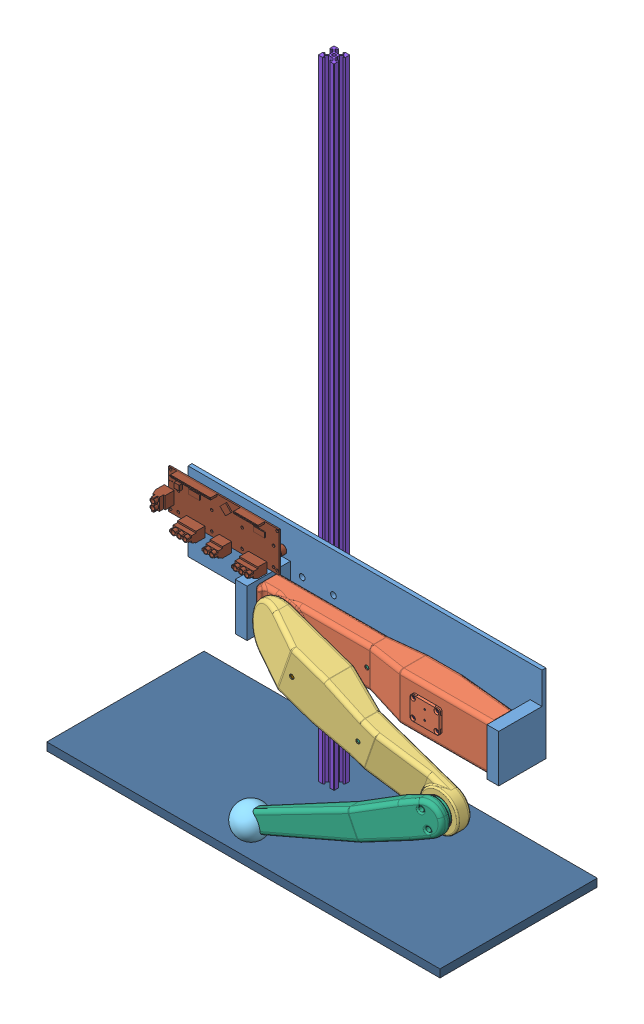
SolidWorks assembly TEST_BENCH_LEG, configuration Default. Lengths in mm.
Overall size (526.75 826.68 209.73).
115 component instances, 48 part files, 14 mates.
Components (placement in the parent):
- FRAME_TEST_BENCH-1: FRAME_TEST_BENCH [Default] at (203.4676 256.1925 358.833) size (450 100 60)
- LIMB_ASSEMBLY-1: LIMB_ASSEMBLY [Default] at (117.0863 75.028 160.078) size (320 252.77 98.98)
  - SHOULDER_ASSEMBLY-1: SHOULDER_ASSEMBLY [Default] at (272.4901 -79.7457 65.6363) x (-1 0 0) z (0 1 0) size (320 40.5 60)
    - SHOULDER_MODULE-1: SHOULDER_MODULE [Default] at (56.0604 170.3399 241.2953) size (320 39 60)
    - Reduction_module-1: Reduction_module [Default] at (136.5679 123.0145 230.5234) x (0.986065 0 -0.166359) z (0.166359 0 0.986065) size (46.5 23.1 46.5)
      - BEARING_MR84-2RS_4x8x2mm.step-2: BEARING_MR84-2RS_4x8x2mm.step [Default] at (6.5822 30.8254 12.0346) x (0.704016 0 0.710185) z (0 -1 0) size (8 8 2)
      - DRIVEN_PULLEY_FIRST_REDUCTION-1: DRIVEN_PULLEY_FIRST_REDUCTION [По умолчанию] at (6.5822 31.8754 12.0346) x (0.983912 0 0.178656) z (0 1 0) size (40 40 8.1)
      - GT2_driving_pulley_second_reduction-1: GT2_driving_pulley_second_reduction [Default] at (6.5822 37.4254 12.0346) x (0.960792 0 -0.27727) z (0 -1 0) size (16 16 16)
      - REDUCTION_SHAFT-1: REDUCTION_SHAFT [Default] at (6.5822 41.3754 12.0346) size (4 23.1 4)
      - BEARING_MR84-2RS_4x8x2mm.step-3: BEARING_MR84-2RS_4x8x2mm.step [Default] at (6.5822 51.9254 12.0346) x (-0.641213 0 -0.767363) z (0 -1 0) size (8 8 2)
      - bearing_spacer_1mm-1: bearing_spacer_1mm [Default] at (6.5822 31.8254 12.0346) x (0.908927 0 0.416955) z (-0.416955 0 0.908927) size (5.2 1 5.2)
      - bearing_spacer_1mm-2: bearing_spacer_1mm [Default] at (6.5822 49.9254 12.0346) size (5.2 1 5.2)
    - Actuator_Module-1: Actuator_Module [Default] at (32.1417 199.8019 282.6675) x (1 0 0) z (0 0 -1) size (50.08 34 54.53)
      - BLDC_Motor_5010-1: BLDC_Motor_5010 [Varsayılan] at (23.9187 12.962 41.3722) size (50.08 20 54.53)
      - MOTOR_SHAFT-1: MOTOR_SHAFT [Default] at (23.9187 29.962 41.3722) x (0.617706 0 0.786409) z (-0.786409 0 0.617706) size (4 34 4)
      - Gates_2GT_20T_Toothed_Pulley-1: Gates_2GT_20T_Toothed_Pulley [Výchozí] at (23.9187 27.862 41.3722) x (0.949687 0 0.313202) z (-0.313202 0 0.949687) size (15 9.4 15)
      - BEARING_MR84-2RS_4x8x2mm.step-4: BEARING_MR84-2RS_4x8x2mm.step [Default] at (23.9187 45.962 41.3722) x (1 0 0) z (0 -1 0) size (8 8 2)
      - pulley-motor-interface-1: pulley-motor-interface [Default] at (23.9187 32.962 41.3722) size (20 2.5 20)
      - bearing_spacer_1mm-1: bearing_spacer_1mm [Default] at (23.9187 43.862 41.3722) size (5.2 1 5.2)
    - Second_reduction_module-1: Second_reduction_module [Default] at (254.9841 185.8856 208.4174) x (-0.999944 0 -0.01057) z (-0.01057 0 0.999944) size (37.7 15.5 37.7)
      - DRIVEN_PULLEY_SECOND_REDUCTION-1: DRIVEN_PULLEY_SECOND_REDUCTION [По умолчанию] at (8.5756 23.3079 32.9704) x (-1 0 0) z (0 -1 0) size (37.7 37.7 15.5)
      - Bearings_6706-2RS.stp-1: Bearings_6706-2RS.stp [Default] at (8.5756 23.7518 32.9704) x (0 1 0) z (0 0 -1) size (3.99 37.01 37.01)
      - Bearings_6706-2RS.stp-2: Bearings_6706-2RS.stp [Default] at (8.5756 12.264 32.9704) x (0 1 0) z (0 0 1) size (3.99 37.01 37.01)
    - Belt-firstt-reduction-1: Belt-firstt-reduction [Default] at (56.0604 157.2025 241.2953) x (0.999993 0 0.003757) z (0 1 0) size (115.2 39.26 6)
    - Belt-second-reduction-1: Belt-second-reduction [Default] at (145.0604 164.4284 241.2953) x (1 0 0.000939) z (-0.000939 0 1) size (127.75 6 39.26)
    - M3x5_socket_head_screw-1: M3x5_socket_head_screw [DIN 7991 - M3 x 8 --- 4.8N] at (64.0604 188.8899 241.2953) x (0 -1 0) z (0.506676 0 0.862137) size (5 5.7 5.7)
    - M3x5_socket_head_screw-2: M3x5_socket_head_screw [DIN 7991 - M3 x 8 --- 4.8N] at (56.0604 188.8899 249.2953) x (0 -1 0) z (0 0 1) size (5 5.7 5.7)
    - M3x5_socket_head_screw-3: M3x5_socket_head_screw [DIN 7991 - M3 x 8 --- 4.8N] at (48.0604 188.8899 241.2953) x (0 -1 0) z (0 0 1) size (5 5.7 5.7)
    - M3x5_socket_head_screw-4: M3x5_socket_head_screw [DIN 7991 - M3 x 8 --- 4.8N] at (56.0604 188.8899 233.2953) x (0 -1 0) z (0 0 1) size (5 5.7 5.7)
    - M3_INSERT.step-1: M3_INSERT.step [Default] at (41.0604 190.8399 230.2953) x (-1 0 0) z (0 0 1) size (4.52 4 4.53)
    - M3_INSERT.step-2: M3_INSERT.step [Default] at (71.0604 190.8399 230.2953) x (1 0 0) z (0 0 -1) size (4.52 4 4.53)
    - M3_INSERT.step-3: M3_INSERT.step [Default] at (41.0604 190.8399 252.2953) x (-1 0 0) z (0 0 1) size (4.52 4 4.53)
    - M3_INSERT.step-4: M3_INSERT.step [Default] at (71.0604 190.8399 252.2953) x (-1 0 0) z (0 0 1) size (4.52 4 4.53)
    - Encoder_magnet-1: Encoder_magnet [Default] at (56.0604 186.8399 241.2953) size (4 1.5 4)
    - AS5048a Magnetic Encoder.step-1: AS5048a Magnetic Encoder.step [Default] at (53.463 190.8399 239.824) x (0 0 1) z (0 -1 0) size (15 17.37 2.2)
      - Component2.step-1: Component2.step [Default] at origin size (0.79 0.74 0.3)
      - Component6.step-1: Component6.step [Default] at origin size (0.79 0.36 0.28)
      - Component7.step-1: Component7.step [Default] at origin size (0.79 0.33 0.28)
      - Component10.step-1: Component10.step [Default] at origin size (0.36 2.99 0.05)
      - Component5.step-1: Component5.step [Default] at origin size (0.79 0.74 0.3)
      - Component9.step-1: Component9.step [Default] at origin size (0.79 0.33 0.28)
      - Component8.step-1: Component8.step [Default] at origin size (0.79 0.36 0.28)
      - Component4.step-1: Component4.step [Default] at origin size (0.36 2.99 0.05)
      - Component3.step-1: Component3.step [Default] at origin size (0.36 2.99 0.05)
      - Component17.step-1: Component17.step [Default] at origin size (5.39 6.68 1.2)
      - Component15.step-1: Component15.step [Default] at origin size (0.36 2.99 0.05)
      - Component14.step-1: Component14.step [Default] at origin size (0.39 2.99 0.05)
      - Component18.step-1: Component18.step [Default] at origin size (0.33 2.67 0.05)
      - Component19.step-1: Component19.step [Default] at origin size (1.7 2.63 0.05)
      - Component11.step-1: Component11.step [Default] at origin size (1.7 2.63 0.05)
      - Component12.step-1: Component12.step [Default] at origin size (0.33 2.99 0.05)
      - Component16.step-1: Component16.step [Default] at origin size (1.7 2.63 0.05)
      - Component13.step-1: Component13.step [Default] at origin size (0.35 2.67 0.05)
      - Magnetic Encoder.step-1: Magnetic Encoder.step [Default] at origin size (15 17.37 1)
    - ENCODER_HOUSING-1: ENCODER_HOUSING [Default] at (56.0604 192.3399 241.2953) x (0 0 -1) z (-1 0 0) size (29 3.5 37)
  - LEG_ASSEMBLY-1: LEG_ASSEMBLY [Default] at (116.0954 382.2297 121.2697) x (0.945086 -0.326822 0) z (-0.326822 -0.945086 0) size (295 43 60)
    - LEG_MODULE-1: LEG_MODULE [Default] at (37.3811 144.4942 237.8663) x (1 0 0) z (0 0 -1) size (295 43 60)
    - Actuator_Module-1: Actuator_Module [Default] at (78.7533 115.0322 213.9476) x (0 0 1) z (-1 0 0) size (50.08 34 54.53)
      - BLDC_Motor_5010-1: BLDC_Motor_5010 [Varsayılan] at (23.9187 12.962 41.3722) size (50.08 20 54.53)
      - MOTOR_SHAFT-1: MOTOR_SHAFT [Default] at (23.9187 29.962 41.3722) x (0.617706 0 0.786409) z (-0.786409 0 0.617706) size (4 34 4)
      - Gates_2GT_20T_Toothed_Pulley-1: Gates_2GT_20T_Toothed_Pulley [Výchozí] at (23.9187 27.862 41.3722) x (0.949687 0 0.313202) z (-0.313202 0 0.949687) size (15 9.4 15)
      - BEARING_MR84-2RS_4x8x2mm.step-4: BEARING_MR84-2RS_4x8x2mm.step [Default] at (23.9187 45.962 41.3722) x (1 0 0) z (0 -1 0) size (8 8 2)
      - pulley-motor-interface-1: pulley-motor-interface [Default] at (23.9187 32.962 41.3722) size (20 2.5 20)
      - bearing_spacer_1mm-1: bearing_spacer_1mm [Default] at (23.9187 43.862 41.3722) size (5.2 1 5.2)
    - Reduction_module-1: Reduction_module [Default] at (112.6677 191.8196 238.1801) x (0.499801 0 0.86614) z (0.86614 0 -0.499801) size (46.5 23.1 46.5)
      - BEARING_MR84-2RS_4x8x2mm.step-2: BEARING_MR84-2RS_4x8x2mm.step [Default] at (6.5822 30.8254 12.0346) x (0.704016 0 0.710185) z (0 -1 0) size (8 8 2)
      - DRIVEN_PULLEY_FIRST_REDUCTION-1: DRIVEN_PULLEY_FIRST_REDUCTION [По умолчанию] at (6.5822 31.8754 12.0346) x (0.983912 0 0.178656) z (0 1 0) size (40 40 8.1)
      - GT2_driving_pulley_second_reduction-1: GT2_driving_pulley_second_reduction [Default] at (6.5822 37.4254 12.0346) x (0.960792 0 -0.27727) z (0 -1 0) size (16 16 16)
      - REDUCTION_SHAFT-1: REDUCTION_SHAFT [Default] at (6.5822 41.3754 12.0346) size (4 23.1 4)
      - BEARING_MR84-2RS_4x8x2mm.step-3: BEARING_MR84-2RS_4x8x2mm.step [Default] at (6.5822 51.9254 12.0346) x (-0.641213 0 -0.767363) z (0 -1 0) size (8 8 2)
      - bearing_spacer_1mm-1: bearing_spacer_1mm [Default] at (6.5822 31.8254 12.0346) x (0.908927 0 0.416955) z (-0.416955 0 0.908927) size (5.2 1 5.2)
      - bearing_spacer_1mm-2: bearing_spacer_1mm [Default] at (6.5822 49.9254 12.0346) size (5.2 1 5.2)
    - AS5048a Magnetic Encoder.step-1: AS5048a Magnetic Encoder.step [Default] at (34.7837 123.9942 239.3377) x (0 0 -1) z (0 1 0) size (15 17.37 2.2)
      - Component2.step-1: Component2.step [Default] at origin size (0.79 0.74 0.3)
      - Component6.step-1: Component6.step [Default] at origin size (0.79 0.36 0.28)
      - Component7.step-1: Component7.step [Default] at origin size (0.79 0.33 0.28)
      - Component10.step-1: Component10.step [Default] at origin size (0.36 2.99 0.05)
      - Component5.step-1: Component5.step [Default] at origin size (0.79 0.74 0.3)
      - Component9.step-1: Component9.step [Default] at origin size (0.79 0.33 0.28)
      - Component8.step-1: Component8.step [Default] at origin size (0.79 0.36 0.28)
      - Component4.step-1: Component4.step [Default] at origin size (0.36 2.99 0.05)
      - Component3.step-1: Component3.step [Default] at origin size (0.36 2.99 0.05)
      - Component17.step-1: Component17.step [Default] at origin size (5.39 6.68 1.2)
      - Component15.step-1: Component15.step [Default] at origin size (0.36 2.99 0.05)
      - Component14.step-1: Component14.step [Default] at origin size (0.39 2.99 0.05)
      - Component18.step-1: Component18.step [Default] at origin size (0.33 2.67 0.05)
      - Component19.step-1: Component19.step [Default] at origin size (1.7 2.63 0.05)
      - Component11.step-1: Component11.step [Default] at origin size (1.7 2.63 0.05)
      - Component12.step-1: Component12.step [Default] at origin size (0.33 2.99 0.05)
      - Component16.step-1: Component16.step [Default] at origin size (1.7 2.63 0.05)
      - Component13.step-1: Component13.step [Default] at origin size (0.35 2.67 0.05)
      - Magnetic Encoder.step-1: Magnetic Encoder.step [Default] at origin size (15 17.37 1)
    - Encoder_magnet-1: Encoder_magnet [Default] at (37.3811 126.4942 237.8663) x (0.937581 0 0.347767) z (-0.347767 0 0.937581) size (4 1.5 4)
    - Second_reduction_module-1: Second_reduction_module [Default] at (236.0673 164.9399 204.9249) x (-0.999994 0 -0.003354) z (-0.003354 0 0.999994) size (37.7 15.5 37.7)
      - DRIVEN_PULLEY_SECOND_REDUCTION-1: DRIVEN_PULLEY_SECOND_REDUCTION [По умолчанию] at (8.5756 23.3079 32.9704) x (-1 0 0) z (0 -1 0) size (37.7 37.7 15.5)
      - Bearings_6706-2RS.stp-1: Bearings_6706-2RS.stp [Default] at (8.5756 23.7518 32.9704) x (0 1 0) z (0 0 -1) size (3.99 37.01 37.01)
      - Bearings_6706-2RS.stp-2: Bearings_6706-2RS.stp [Default] at (8.5756 12.264 32.9704) x (0 1 0) z (0 0 1) size (3.99 37.01 37.01)
    - Belt-first-reduction-1: Belt-first-reduction [Default] at (37.3811 151.4942 237.8663) x (0.999999 0 -0.001141) z (0 1 0) size (115.2 39.26 6)
    - Belt-second-reduction-1: Belt-second-reduction [Default] at (126.3811 144.3942 237.8663) x (1 0 0.000599) z (-0.000599 0 1) size (127.75 6 39.26)
    - ENCODER_HOUSING-1: ENCODER_HOUSING [Default] at (37.3811 122.4942 237.8663) x (0 0 1) z (-1 0 0) size (29 3.5 37)
    - M3_INSERT.step-2: M3_INSERT.step [Default] at (52.3811 123.9942 248.8663) size (4.52 4 4.53)
    - M3_INSERT.step-3: M3_INSERT.step [Default] at (22.3811 123.9942 248.8663) size (4.52 4 4.53)
    - M3_INSERT.step-4: M3_INSERT.step [Default] at (52.3811 123.9942 226.8663) size (4.52 4 4.53)
    - M3_INSERT.step-5: M3_INSERT.step [Default] at (22.3811 123.9942 226.8663) size (4.52 4 4.53)
  - LOWER_LEG_ASSEMBLY-1: LOWER_LEG_ASSEMBLY [Default] at (180.0931 47.1809 239.1676) x (-0.894884 -0.446298 0) z (-0.446298 0.894884 0) size (285 40.5 40.01)
    - foot-1: foot [Default] at (163.4965 57.2841 -0.5063) x (0 1 0) z (0 0 -1) size (40 38.91 40)
    - LOWER_LEG_MODULE-1: LOWER_LEG_MODULE [Default] at (3.4965 60.7841 -0.4954) size (265 33.98 40)
- sliding_plate-1: sliding_plate [Default] at (143.4676 256.1925 358.833) x (1 0 0) z (0 1 0) size (65.5 9 65.5)
- 2020V-Slot-Profile-1: 2020V-Slot-Profile [Default] at (144.5376 31.9753 344.333) x (1 0 0) z (0 1 0) size (20 20 800)
- sliding_wheel.step-1: sliding_wheel.step [Default] at (123.6176 236.1925 349.833) x (-0.923839 -0.382781 0) z (0.382781 -0.923839 0) size (24 11 24)
- sliding_wheel.step-2: sliding_wheel.step [Default] at (123.6176 276.1925 349.833) x (-0.923839 -0.382781 0) z (0.382781 -0.923839 0) size (24 11 24)
- sliding_wheel.step-3: sliding_wheel.step [Default] at (163.3176 236.1925 349.833) x (-0.923839 -0.382781 0) z (0.382781 -0.923839 0) size (24 11 24)
- sliding_wheel.step-4: sliding_wheel.step [Default] at (163.3176 276.1925 349.833) x (-0.923839 -0.382781 0) z (0.382781 -0.923839 0) size (24 11 24)
- BASE_LEG_TEST_BENCH-1: BASE_LEG_TEST_BENCH [Default] at (151.7174 5.2956 366.7965) size (500 10 200)
- Motor driver ODRIVE V3.6.stp-1: Motor driver ODRIVE V3.6.stp [Default] at (52.2613 296.9342 409.2091) size (146 55.7 33.72)
Mates (geometry in assembly coordinates):
- Concentric1: concentric anti-aligned: cylinder of sliding_plate-1 through (123.6176 236.1925 349.833) axis (0 0 1) radius 4.5; cylinder of sliding_wheel.step-1 through (123.6176 236.1925 349.833) axis (0 0 -1) radius 12
- Coincident1: coincident anti-aligned: plane of sliding_plate-1 through (123.6176 236.1925 349.833) normal (0 0 -1); plane of sliding_wheel.step-1 through (123.6176 236.1925 349.833) normal (0 0 1)
- Concentric2: concentric anti-aligned: cylinder of sliding_plate-1 through (163.3176 236.1925 349.833) axis (0 0 1) radius 4.5; cylinder of sliding_wheel.step-3 through (163.3176 236.1925 349.833) axis (0 0 -1) radius 12
- Coincident2: coincident anti-aligned: plane of sliding_plate-1 through (163.3176 236.1925 349.833) normal (0 0 -1); plane of sliding_wheel.step-3 through (163.3176 236.1925 349.833) normal (0 0 1)
- Coincident3: coincident anti-aligned: plane of sliding_plate-1 through (123.6176 276.1925 349.833) normal (0 0 -1); plane of sliding_wheel.step-2 through (123.6176 276.1925 349.833) normal (0 0 1)
- Concentric3: concentric anti-aligned: cylinder of sliding_plate-1 through (123.6176 276.1925 349.833) axis (0 0 1) radius 4.5; cylinder of sliding_wheel.step-2 through (123.6176 276.1925 349.833) axis (0 0 -1) radius 12
- Concentric4: concentric anti-aligned: cylinder of sliding_plate-1 through (163.3176 276.1925 349.833) axis (0 0 1) radius 4.5; cylinder of sliding_wheel.step-4 through (163.3176 276.1925 349.833) axis (0 0 -1) radius 12
- Coincident4: coincident anti-aligned: plane of sliding_plate-1 through (163.3176 276.1925 349.833) normal (0 0 -1); plane of sliding_wheel.step-4 through (163.3176 276.1925 349.833) normal (0 0 1)
- Tangent4: tangent anti-aligned: plane of 2020V-Slot-Profile-1 through (135.9926 831.9753 347.458) normal (-0.707107 0 -0.707107); cone of sliding_wheel.step-2 through (123.6176 276.1925 348.833) axis (0 0 1)
- Tangent5: tangent anti-aligned: plane of 2020V-Slot-Profile-1 through (135.9926 831.9753 347.458) normal (-0.707107 0 -0.707107); cone of sliding_wheel.step-1 through (123.6176 236.1925 348.833) axis (0 0 1)
- Tangent6: tangent anti-aligned: plane of 2020V-Slot-Profile-1 through (135.9926 831.9753 341.208) normal (-0.707107 0 0.707107); cone of sliding_wheel.step-2 through (123.6176 276.1925 339.833) axis (0 0 -1)
- Concentric5: concentric anti-aligned: cylinder of FRAME_TEST_BENCH-1 through (123.6176 256.1925 358.833) axis (0 0 1) radius 3.6; cylinder of sliding_plate-1 through (123.6176 256.1925 358.833) axis (0 0 -1) radius 3.6
- Concentric6: concentric anti-aligned: cylinder of FRAME_TEST_BENCH-1 through (163.3176 256.1925 358.833) axis (0 0 1) radius 3.6; cylinder of sliding_plate-1 through (163.3176 256.1925 358.833) axis (0 0 -1) radius 3.6
- Coincident5: coincident anti-aligned: plane of FRAME_TEST_BENCH-1 through (203.4676 256.1925 358.833) normal (0 0 -1); plane of sliding_plate-1 through (143.4676 256.1925 358.833) normal (0 0 1)
